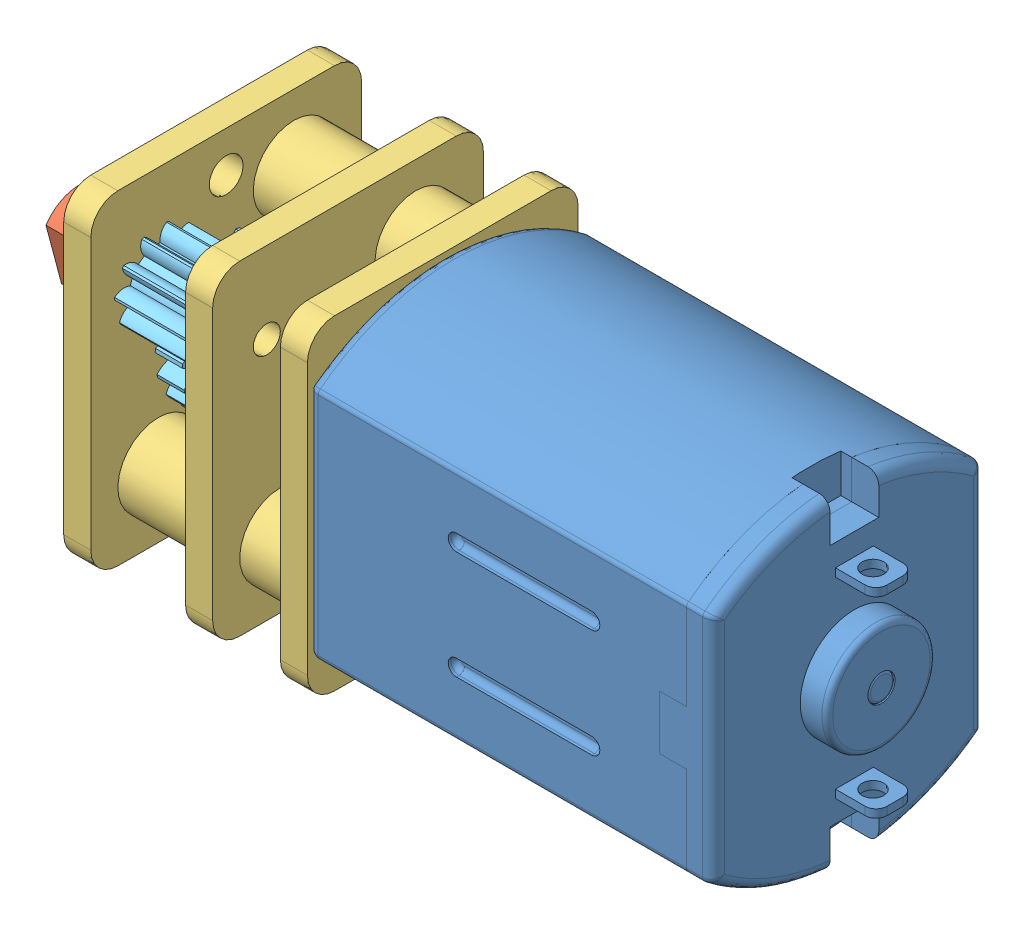
SolidWorks assembly n20, configuration 默认. Lengths in mm.
Overall size (29.9 12.14 10.87).
11 component instances, 5 part files, 21 mates.
Components (placement in the parent):
- motor-1: motor [默认] at (-3.4114 0.0905 -5.0483) size (19.5 12 10)
- n20_shaft-1: n20_shaft [默认] at (-11.4114 0.0905 -0.0483) x (0 -0.966302 -0.257412) z (0 0.257412 -0.966302) size (3 5.4 3)
- n20_gearbox-1: n20_gearbox [默认] at (-11.4114 0.0905 -0.0483) x (0 1 0) z (-1 0 0) size (12 10 9.7)
- cross recessed countersunk head screws gb1-1: cross recessed countersunk head screws gb1 [GB_CROSS_SCREWS_TYPE4 M1.6X3-2  H type-N] at (-12.4614 -3.4095 2.4517) size (3 2.7 2.7)
- cross recessed countersunk head screws gb1-2: cross recessed countersunk head screws gb1 [GB_CROSS_SCREWS_TYPE4 M1.6X3-2  H type-N] at (-12.4614 3.5905 -2.5483) x (1 0 0) z (0 0.116872 0.993147) size (3 2.7 2.7)
- spur gear_gb-1: spur gear_gb [GB - Spur gear 0.25M 10T 20PA 2FW ---S10A75H50L1.0N] at (-8.4114 -2.9095 -2.5483) x (1 0 0) z (0 -0.845955 0.533254) size (2 2.87 3)
- spur gear_gb-2: spur gear_gb [GB - Spur gear 0.25M 10T 20PA 2FW ---S10A75H50L1.0N] at (-4.4114 0.0905 -0.0483) x (-1 0 0) z (0 0.404067 -0.914729) size (2 2.87 3)
- spur gear_gb-4: spur gear_gb [GB - Spur gear 0.25M 16T 20PA 2FW ---S16A75H50L1.0N] at (-6.4114 -2.9095 -2.5483) x (1 0 0) z (0 -0.712706 0.701463) size (2 4.44 4.44)
- spur gear_gb-6: spur gear_gb [GB - Spur gear 0.25M 19T 20PA 2FW ---S19A75H50L1.0N] at (-9.9114 0.0905 -0.0483) x (1 0 0) z (0 0.321468 -0.94692) size (2 5.22 5.24)
- spur gear_gb-8: spur gear_gb [GB - Spur gear 0.25M 11T 20PA 3FW ---S11A75H50L1.0N] at (-10.9114 3.0905 2.9517) x (1 0 0) z (0 -0.604063 0.796937) size (3 3.2 3.23)
- spur gear_gb-10: spur gear_gb [GB - Spur gear 0.25M 19T 20PA 1FW ---S19A75H50L1.0N] at (-11.4114 0.0905 -0.0483) x (1 0 0) z (0 -0.330889 0.94367) size (1 5.22 5.24)
Mates (geometry in assembly coordinates):
- 同心1: concentric anti-aligned: cylinder of motor-1 through (-6.4114 0.0905 -0.0483) axis (1 0 0) radius 0.5; cylinder of n20_gearbox-1 through (-3.4114 0.0905 -0.0483) axis (-1 0 0) radius 0.5329
- 重合1: coincident anti-aligned: plane of motor-1 through (-3.4114 -5.9095 4.9517) normal (-1 0 0); plane of n20_gearbox-1 through (-3.4114 0.0905 -0.0483) normal (1 0 0)
- 重合2: coincident aligned: plane of motor-1 through (-3.4114 0.0905 4.9517) normal (0 0 1); plane of n20_gearbox-1 through (-3.4114 6.0905 4.9517) normal (0 0 1)
- 同心2: concentric aligned: cylinder of n20_shaft-1 through (-16.8114 0.0905 -0.0483) axis (1 0 0) radius 1.5; cylinder of n20_gearbox-1 through (-12.4114 0.0905 -0.0483) axis (1 0 0) radius 1.5
- 重合3: coincident aligned: plane of n20_shaft-1 through (-11.4114 0.0905 -0.0483) normal (1 0 0); plane of n20_gearbox-1 through (-11.4114 0.0905 -0.0483) normal (1 0 0)
- 同心3: concentric anti-aligned: cylinder of n20_gearbox-1 through (-7.9114 3.5905 -2.5483) axis (-1 0 0) radius 0.9; cone of cross recessed countersunk head screws gb1-2 through (-11.4614 3.5905 -2.5483) axis (1 0 0)
- 重合4: coincident aligned: cone of n20_gearbox-1 through (-12.4114 3.5905 -2.5483) axis (1 0 0); cone of cross recessed countersunk head screws gb1-2 through (-11.4614 3.5905 -2.5483) axis (1 0 0)
- 同心8: concentric anti-aligned: cylinder of n20_gearbox-1 through (-7.9114 -3.4095 2.4517) axis (-1 0 0) radius 0.9; cylinder of cross recessed countersunk head screws gb1-1 through (-7.9456 -3.4095 2.4517) axis (1 0 0) radius 0.8
- 重合5: coincident aligned: cone of n20_gearbox-1 through (-12.4114 -3.4095 2.4517) axis (1 0 0); cone of cross recessed countersunk head screws gb1-1 through (-11.4614 -3.4095 2.4517) axis (1 0 0)
- 同心10: concentric aligned: cylinder of motor-1 through (-6.4114 0.0905 -0.0483) axis (1 0 0) radius 0.5; cylinder of spur gear_gb-2 through (-54.4115 0.0905 -0.0483) axis (1 0 0) radius 0.5
- 同心11: concentric aligned: cylinder of n20_gearbox-1 through (-3.4114 -2.9095 -2.5483) axis (-1 0 0) radius 0.5; cylinder of spur gear_gb-4 through (43.5886 -2.9095 -2.5483) axis (-1 0 0) radius 0.5
- 重合6: coincident anti-aligned: plane of n20_gearbox-1 through (-4.4114 0.0905 -0.0483) normal (-1 0 0); plane of spur gear_gb-4 through (-4.4114 -2.9095 -2.5483) normal (1 0 0)
- 同心12: concentric aligned: cylinder of n20_gearbox-1 through (-6.9114 0.0905 -0.0483) axis (-1 0 0) radius 0.5; cylinder of spur gear_gb-6 through (40.0886 0.0905 -0.0483) axis (-1 0 0) radius 0.5
- 重合7: coincident anti-aligned: plane of n20_gearbox-1 through (-7.9114 0.0905 -0.0483) normal (-1 0 0); plane of spur gear_gb-6 through (-7.9114 0.0905 -0.0483) normal (1 0 0)
- 同心13: concentric aligned: cylinder of spur gear_gb-1 through (41.5886 -2.9095 -2.5483) axis (-1 0 0) radius 0.5; cylinder of spur gear_gb-4 through (43.5886 -2.9095 -2.5483) axis (-1 0 0) radius 0.5
- 重合8: coincident anti-aligned: plane of spur gear_gb-1 through (-6.4114 -2.9095 -2.5483) normal (1 0 0); plane of spur gear_gb-4 through (-6.4114 -2.9095 -2.5483) normal (-1 0 0)
- 同心14: concentric aligned: cylinder of n20_gearbox-1 through (-6.9114 3.0905 2.9517) axis (-1 0 0) radius 0.5; cylinder of spur gear_gb-8 through (39.0886 3.0905 2.9517) axis (-1 0 0) radius 0.5
- 同心15: concentric aligned: cylinder of spur gear_gb-6 through (40.0886 0.0905 -0.0483) axis (-1 0 0) radius 0.5; cylinder of spur gear_gb-10 through (38.5886 0.0905 -0.0483) axis (-1 0 0) radius 0.5
- 重合9: coincident anti-aligned: plane of n20_gearbox-1 through (-7.9114 0.0905 -0.0483) normal (-1 0 0); plane of spur gear_gb-8 through (-7.9114 3.0905 2.9517) normal (1 0 0)
- 重合10: coincident anti-aligned: plane of n20_gearbox-1 through (-11.4114 0.0905 -0.0483) normal (1 0 0); plane of spur gear_gb-10 through (-11.4114 0.0905 -0.0483) normal (-1 0 0)
- 重合11: coincident anti-aligned: plane of n20_gearbox-1 through (-4.4114 0.0905 -0.0483) normal (-1 0 0); plane of spur gear_gb-2 through (-4.4114 0.0905 -0.0483) normal (1 0 0)
